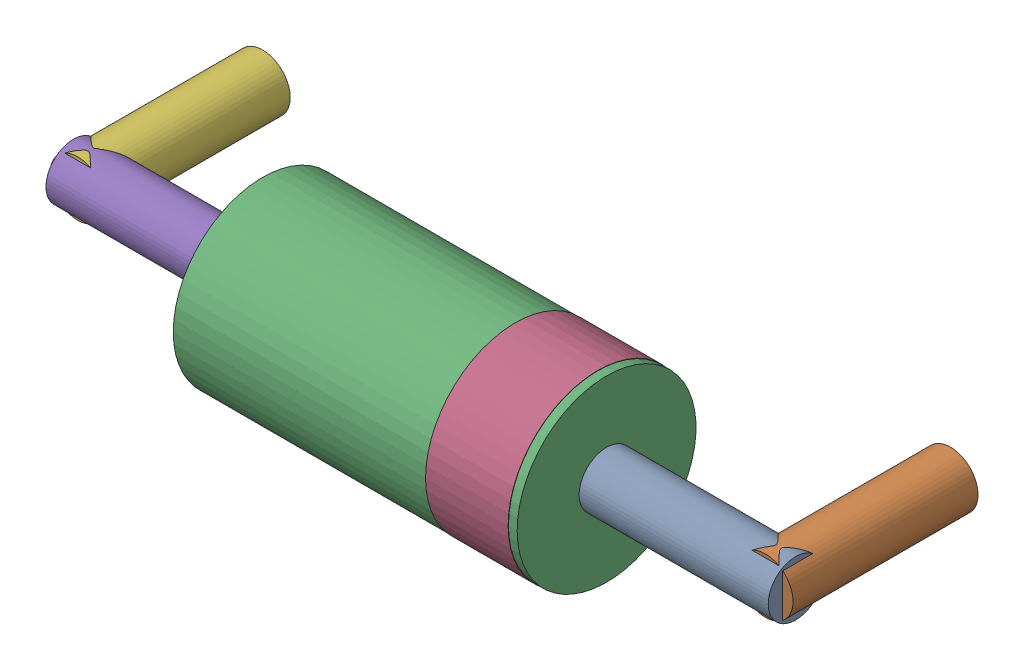
SolidWorks assembly D7, configuration Default. Lengths in mm.
Overall size (10.8 2.61 3.81).
12 component instances, 6 part files, 0 mates.
Components (placement in the parent):
- -1733042672-1: -1733042672 [Default] at (501.2503 292.9977 1.5) x (0 0 -1) z (-1 0 0) size (0.8 0.8 2.75)
  - Cylinder-1: Cylinder [Default] at origin size (0.8 0.8 2.75)
- -1733042992-1: -1733042992 [Default] at (500.9999 292.9999 -1) x (-1 0 0) z (0 0 1) size (0.8 0.8 2.69)
  - Cylinder_2-1: Cylinder_2 [Default] at origin size (0.8 0.8 2.69)
- -1733042432-1: -1733042432 [Default] at (498.5001 292.9975 1.5) x (0 0 -1) z (-1 0 0) size (2.6 2.6 5)
  - Cylinder_3-1: Cylinder_3 [Default] at origin size (2.6 2.6 5)
- -1733042152-1: -1733042152 [Default] at (498.3731 292.9976 1.5) x (0 0 -1) z (-1 0 0) size (2.61 2.61 1.2)
  - Cylinder_4-1: Cylinder_4 [Default] at origin size (2.61 2.61 1.2)
- -1733041072-1: -1733041072 [Default] at (490.7497 293.0023 1.5) x (0 0 -1) z (1 0 0) size (0.8 0.8 2.75)
  - Cylinder_5-1: Cylinder_5 [Default] at origin size (0.8 0.8 2.75)
- -1733041192-1: -1733041192 [Default] at (491.0001 293.0001 -1) x (1 0 0) z (0 0 1) size (0.8 0.8 2.69)
  - Cylinder_6-1: Cylinder_6 [Default] at origin size (0.8 0.8 2.69)
